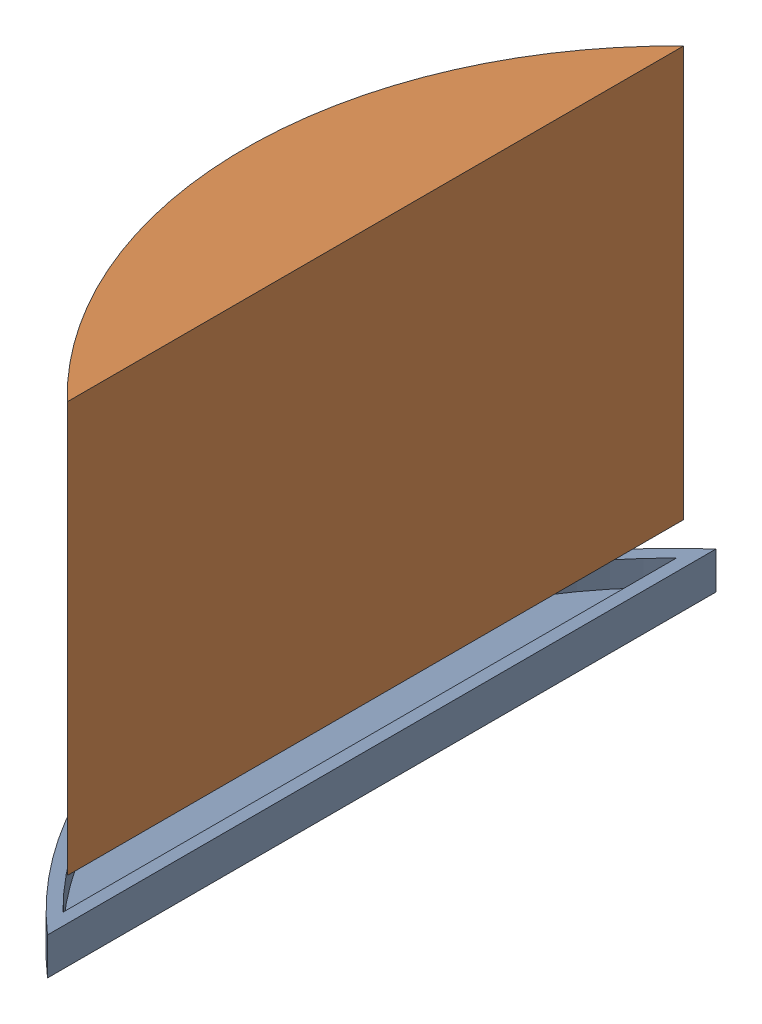
SolidWorks assembly Housing Assembly, configuration Default. Lengths in mm.
Overall size (91.44 82.2 113.79).
2 component instances, 2 part files, 2 mates.
Components (placement in the parent):
- Astronaut House Cap-1: Astronaut House Cap [Default] at (-23.8746 18.3707 -50.6896) size (25.84 6.35 113.79)
- AstronautHouse-1: AstronautHouse [Default] at (25.8538 94.2252 6.2064) x (0.876226 0 0.481901) z (0.481901 0 -0.876226) size (53.79 69.85 91.93)
Mates (geometry in assembly coordinates):
- Concentric1: concentric anti-aligned: circle of Astronaut House Cap-1; circle of AstronautHouse-1
- Parallel1: parallel aligned: line of Astronaut House Cap-1 through (-23.8746 18.3707 -50.6896) axis (0 0 1); line of AstronautHouse-1 through (-24.9462 30.7252 -46.2532) axis (0 0 1)
